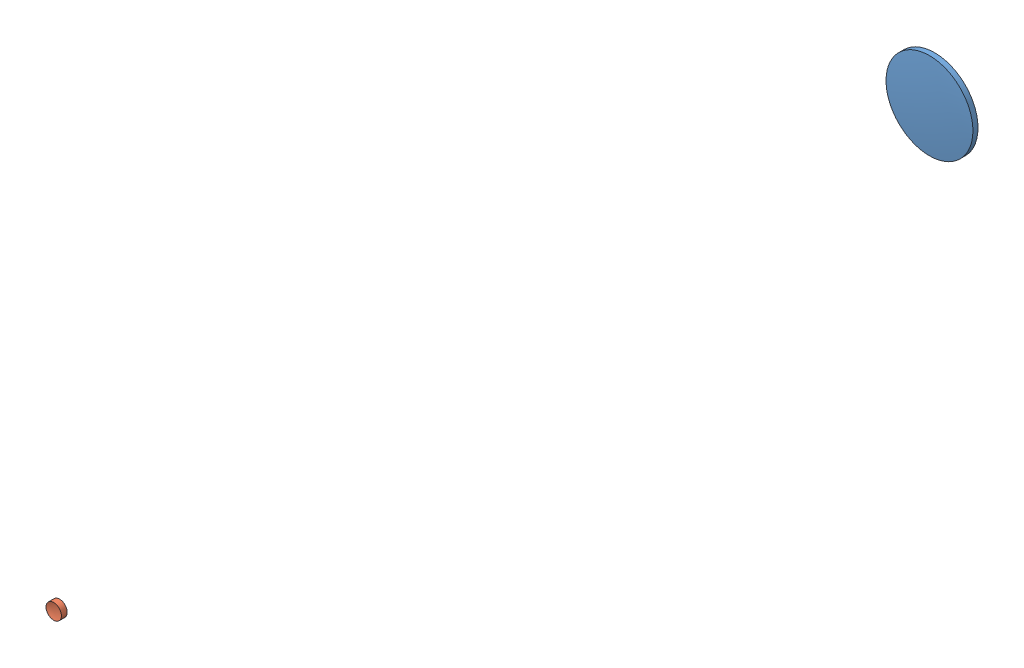
SolidWorks assembly Assem1, configuration Default. Lengths in mm.
Overall size (50.8 50.8 515.43).
2 component instances, 2 part files, 2 mates.
Components (placement in the parent):
- LA1380-A-Solidworks-1: LA1380-A-Solidworks [Default] at (-6.309 24.5055 47.3585) size (50.8 50.8 4.25)
- LD2568-A-Solidworks-1: LD2568-A-Solidworks [Default] at (-6.309 24.5055 558.9475) size (9 9 3.44)
Mates (geometry in assembly coordinates):
- Concentric1: concentric aligned: cylinder of LA1380-A-Solidworks-1 through (-6.309 24.5055 51.6667) axis (0 0 1) radius 25.4; cylinder of LD2568-A-Solidworks-1 through (-6.309 24.5055 563.0199) axis (0 0 1) radius 4.5
- Distance1: distance = 509 mm aligned: plane of LA1380-A-Solidworks-1 through (-6.309 24.5055 48.2279) normal (0 0 1); plane of LD2568-A-Solidworks-1 through (-6.309 24.5055 557.2279) normal (0 0 1)
